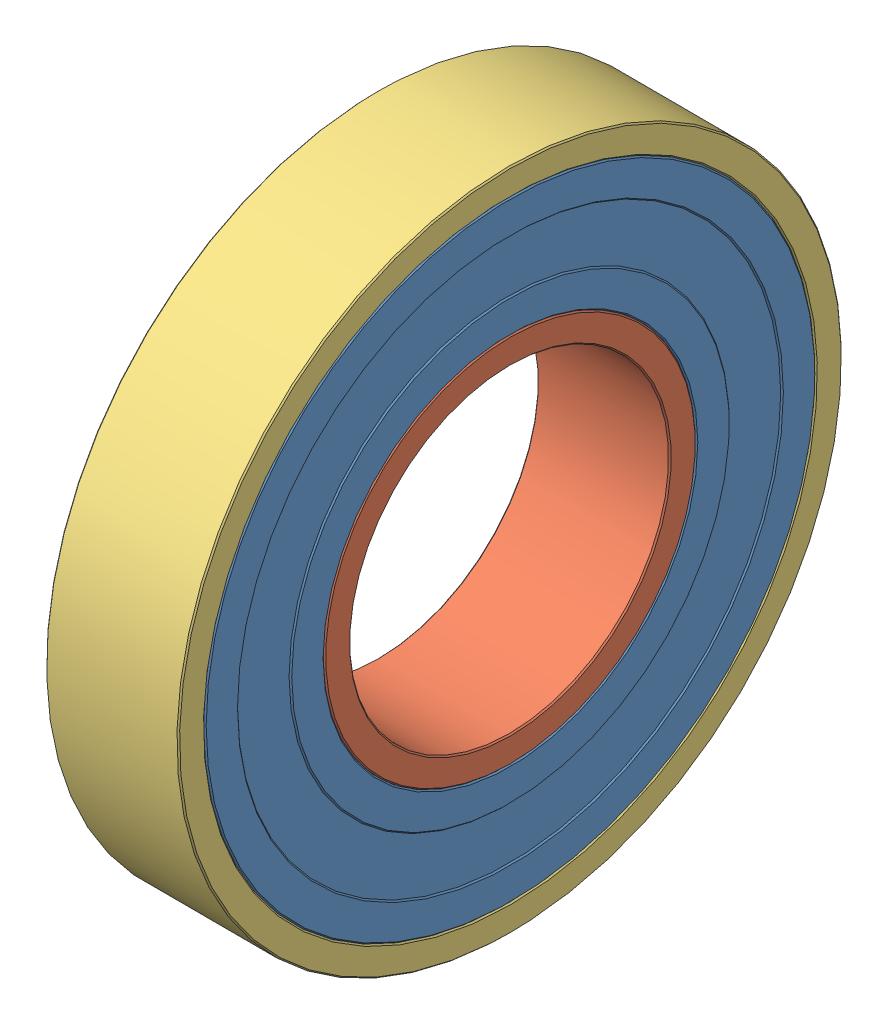
SolidWorks assembly Assieme3, configuration Default. Lengths in mm.
Overall size (22.73 25 25).
3 component instances, 3 part files, 4 mates.
Components (placement in the parent):
- Parte3SM-1: Parte3SM [Default] at (0.146 -0.6226 23) size (13.43 23 23)
- Parte2SM-1: Parte2SM [Default] at (5.5178 -0.6226 23) size (9.29 15.6 15.6)
- Parte1SM-1: Parte1SM [Default] at (6.6446 -0.6226 23) x (0 0 -1) z (1 0 0) size (25 25 14.29)
Mates (geometry in assembly coordinates):
- Concentrico1: concentric anti-aligned: cylinder of Parte3SM-1 through (0.146 -0.6226 23) axis (1 0 0) radius 10.7; cylinder of Parte1SM-1 through (6.6446 -0.6226 23) axis (-1 0 0) radius 10.7
- Coincidente1: coincident aligned: plane of Parte3SM-1 through (1.0812 10.8774 23) normal (-1 0 0); plane of Parte1SM-1 through (1.0812 11.8774 23) normal (-1 0 0)
- Concentrico2: concentric aligned: cylinder of Parte3SM-1 through (0.146 -0.6226 23) axis (1 0 0) radius 7; cylinder of Parte2SM-1 through (5.5178 -0.6226 23) axis (1 0 0) radius 7
- Coincidente2: coincident aligned: plane of Parte3SM-1 through (1.0812 7.6576 23) normal (-1 0 0); plane of Parte2SM-1 through (1.0812 6.3774 23) normal (-1 0 0)
